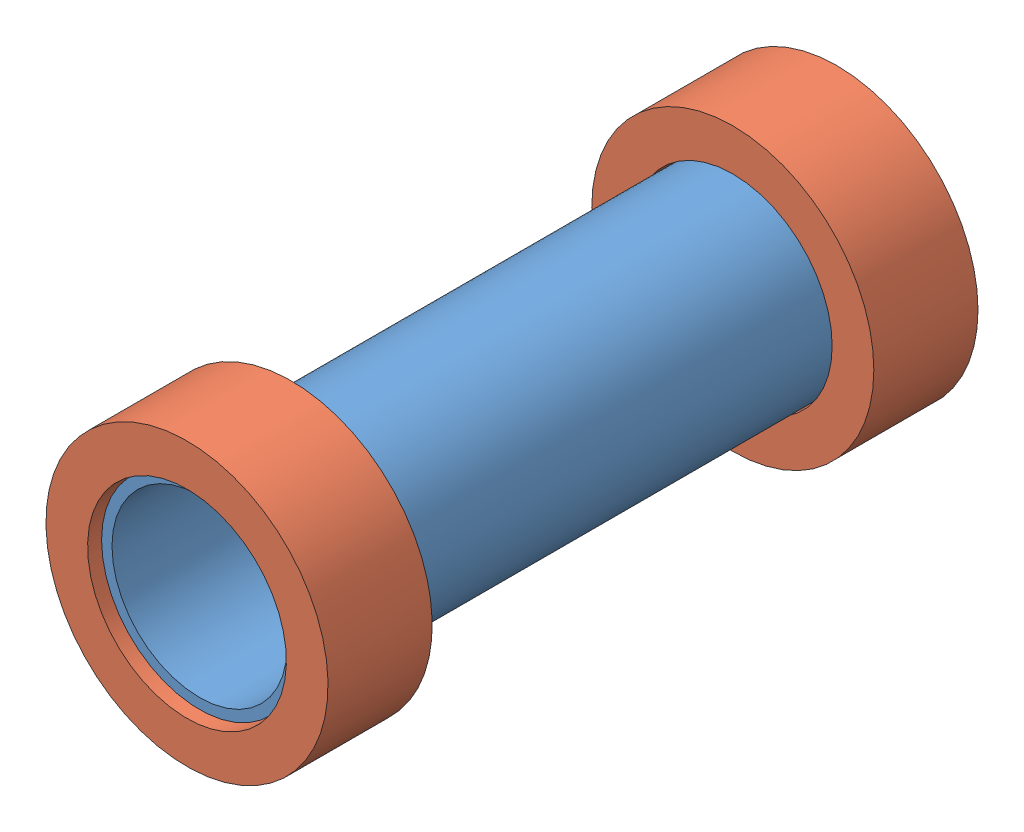
SolidWorks assembly StorageCapsule, configuration Default. Lengths in mm.
Overall size (22.47 22.47 39.62).
3 component instances, 2 part files, 4 mates.
Components (placement in the parent):
- Capsule Body-1: Capsule Body [Default] at (-35.2494 1.4555 -1.4383) size (11.94 11.94 38.1)
- Caps-1: Caps [Default] at (-35.2494 1.4555 37.4237) x (-0.923728 -0.383049 0) z (0 0 -1) size (17.2 17.2 6.35)
- Caps-2: Caps [Default] at (-35.2494 1.4555 -2.2003) size (17.2 17.2 6.35)
Mates (geometry in assembly coordinates):
- Distance1: distance = 0.762 mm aligned: plane of Caps-1 through (-35.2494 1.4555 37.4237) normal (0 0 1); plane of Capsule Body-1 through (-35.2494 1.4555 36.6617) normal (0 0 1)
- Concentric1: concentric aligned: cylinder of Capsule Body-1 through (-35.2494 1.4555 -1.4383) axis (0 0 1) radius 5.334; cylinder of Caps-1 through (-35.2494 1.4555 31.0737) axis (0 0 1) radius 6.0585
- Concentric2: concentric anti-aligned: circle of Capsule Body-1; cylinder of Caps-2 through (-35.2494 1.4555 4.1497) axis (0 0 -1) radius 6.0585
- Distance2: distance = 0.762 mm aligned: plane of Caps-2 through (-35.2494 1.4555 -2.2003) normal (0 0 -1); plane of Capsule Body-1 through (-35.2494 1.4555 -1.4383) normal (0 0 -1)
